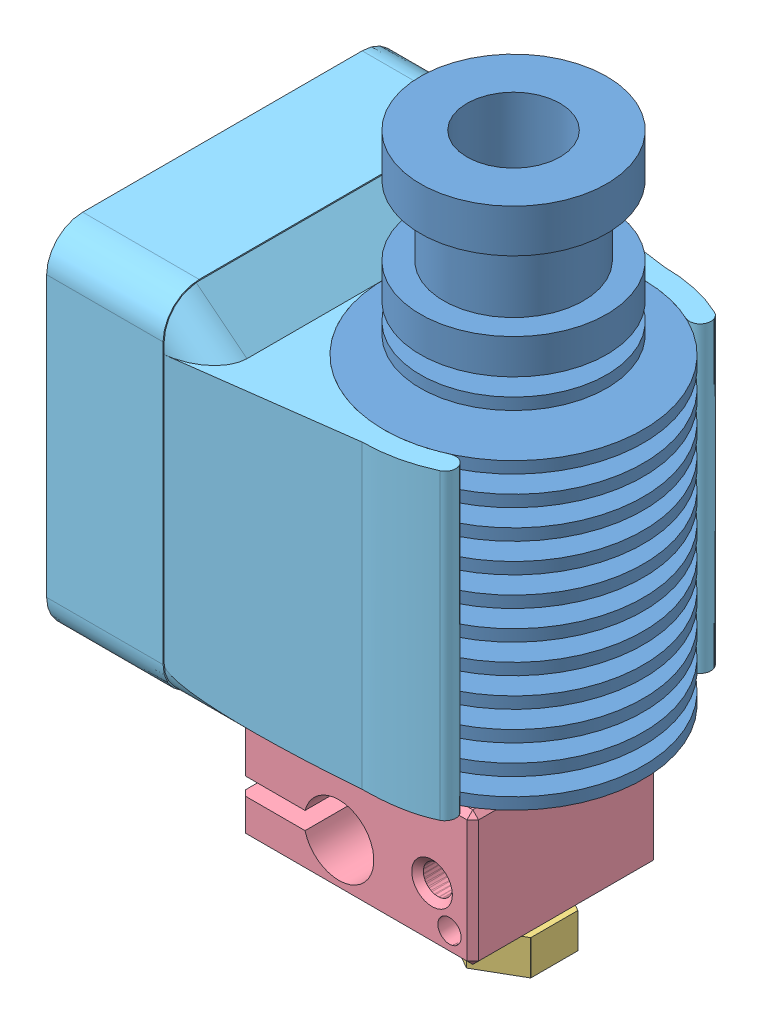
SolidWorks assembly Hotend E3D V6, configuration По умолчанию. Lengths in mm.
Overall size (36.15 62.3 30.2).
5 component instances, 5 part files, 13 mates.
Components (placement in the parent):
- Радиатор V6.4-1: Радиатор V6.4 [По умолчанию] at origin size (22.3 42.7 22.3)
- Держатель сопла V6.5-1: Держатель сопла V6.5 [По умолчанию] at (0 -7.1 0) size (7 21.9 7)
- Сопло V6.3 1,75 мм-1: Сопло V6.3 1,75 мм [По умолчанию] at (0 -19.6 0) size (7 12.5 8.08)
- Открытый обогревательный блок  V6.4-1: Открытый обогревательный блок  V6.4 [По умолчанию] at (-5.5 -7.85 0) x (0 0 1) z (-1 0 0) size (16 11.5 20)
- Куллер-1: Куллер [По умолчанию] at (0 13 0) x (0 0 1) z (-1 0 0) size (30.2 30.2 31)
Mates (geometry in assembly coordinates):
- Концентричный1: concentric aligned: cylinder of Радиатор V6.4-1 through (0 0 0) axis (0 -1 0) radius 2.9585; cylinder of Держатель сопла V6.5-1 through (0 -7.1 0) axis (0 -1 0) radius 3.5
- Совпадение1: coincident aligned: plane of Радиатор V6.4-1 through (0 0 2.1) normal (0 -1 0); plane of Держатель сопла V6.5-1 through (0 0 1.4) normal (0 -1 0)
- Совпадение2: coincident aligned: plane of Радиатор V6.4-1 through (0 0 0) normal (1 0 0); plane of Держатель сопла V6.5-1 through (0 -7.1 0) normal (1 0 0)
- Концентричный2: concentric anti-aligned: cylinder of Держатель сопла V6.5-1 through (0 -7.1 0) axis (0 -1 0) radius 3; cylinder of Открытый обогревательный блок  V6.4-1 through (0 -2.1 0) axis (0 1 0) radius 2.5
- Параллельность1: parallel aligned: plane of Радиатор V6.4-1 through (0 0 0) normal (0 0 1); plane of Открытый обогревательный блок  V6.4-1 through (-5.5 -7.85 0) normal (0 0 1)
- Концентричный3: concentric anti-aligned: cylinder of Сопло V6.3 1,75 мм-1 through (0 -19.6 0) axis (0 -1 0) radius 3; cylinder of Открытый обогревательный блок  V6.4-1 through (0 -2.1 0) axis (0 1 0) radius 2.5
- Совпадение6: coincident aligned: plane of Радиатор V6.4-1 through (0 0 0) normal (1 0 0); plane of Сопло V6.3 1,75 мм-1 through (0 -19.6 0) normal (1 0 0)
- Совпадение7: coincident anti-aligned: plane of Держатель сопла V6.5-1 through (0 -7.1 1) normal (0 -1 0); plane of Сопло V6.3 1,75 мм-1 through (0 -7.1 2.5) normal (0 1 0)
- Совпадение9: coincident aligned: plane of Держатель сопла V6.5-1 through (0 -2.1 3) normal (0 1 0); plane of Открытый обогревательный блок  V6.4-1 through (-4.5 -2.1 -8) normal (0 1 0)
- Концентричный4: concentric aligned: cylinder of Радиатор V6.4-1 through (0 0 0) axis (0 -1 0) radius 11.15; cylinder of Куллер-1 through (0 26 0) axis (0 -1 0) radius 11.15
- Совпадение10: coincident aligned: plane of Радиатор V6.4-1 through (0 0 2.1) normal (0 -1 0); plane of Куллер-1 through (2.5375 0 5.4784) normal (0 -1 0)
- Совпадение11: coincident aligned: plane of Радиатор V6.4-1 through (0 0 0) normal (0 0 1); plane of Куллер-1 through (0 13 0) normal (0 0 1)
- Совпадение12: coordinate: point of Радиатор V6.4-1; point of assembly
